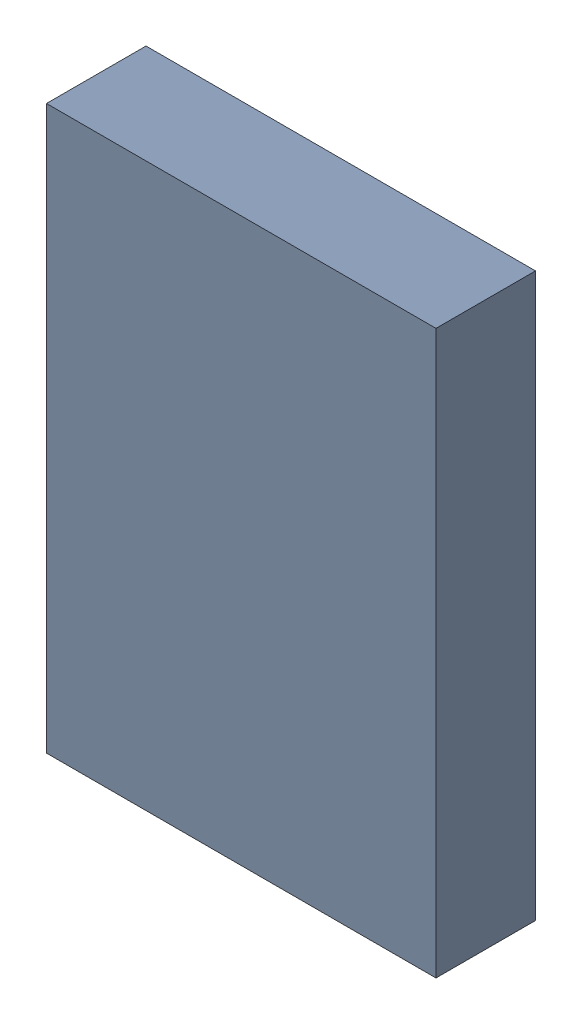
SolidWorks assembly BrandNewKicksKanaloa_v2.0.0_Power, configuration Default. Lengths in mm.
Overall size (4.5 6.5 1.15).
2 component instances, 1 part files, 0 mates.
Components (placement in the parent):
- 425993472-1: 425993472 [Default] at (137.0468 95.6544 0.05) size (4.5 6.5 1.15)
  - Extruded_17-1: Extruded_17 [Default] at origin size (4.5 6.5 1.15)
